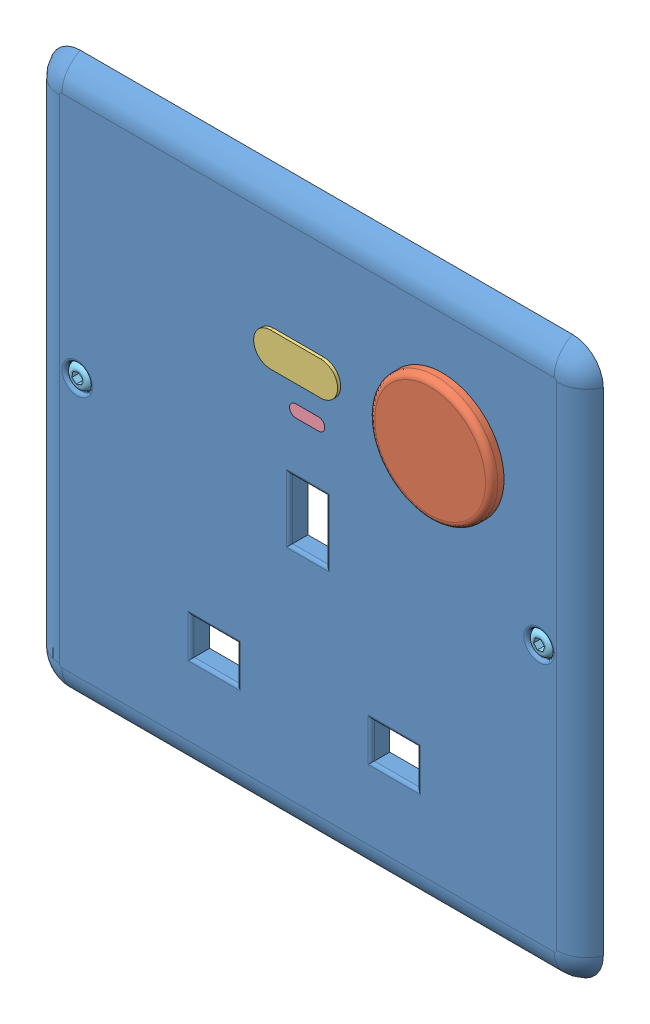
SolidWorks assembly OneSwitchAss, configuration Default. Lengths in mm.
Overall size (90 90 5).
6 component instances, 5 part files, 9 mates.
Components (placement in the parent):
- OneSwitch-1: OneSwitch [Default] at (-65.1599 0.035 9.5843) size (90 90 3)
- Button20mm-1: Button20mm [Default] at (12.0558 -2.4455 9.5843) x (0.673243 -0.739421 0) z (0 0 1) size (20 20 5)
- CoverFilter-1: CoverFilter [Default] at (31.6648 18.0079 12.7033) size (13.66 5.5 0.5)
- LEDindicator-1: LEDindicator [Default] at (15.6237 20.3006 9.5843) size (5.72 2 3)
- Screw4mm-1: Screw4mm [Default] at (-50.7894 -10.21 12.5843) x (-0.938133 -0.346274 0) z (0 0 -1) size (4 4 3)
- Screw4mm-2: Screw4mm [Default] at (24.0575 -4.8541 12.5843) x (-0.666788 0.745248 0) z (0 0 -1) size (4 4 3)
Mates (geometry in assembly coordinates):
- Concentric2: concentric anti-aligned: cylinder of OneSwitch-1 through (12.3917 13.0449 9.5843) axis (0 0 1) radius 10; cylinder of Button20mm-1 through (12.3917 13.0449 14.5843) axis (0 0 -1) radius 10
- Concentric3: concentric aligned: cylinder of OneSwitch-1 through (28.1038 -7.3722 9.5843) axis (0 0 1) radius 2; cylinder of Screw4mm-2 through (28.1038 -7.3722 9.5843) axis (0 0 1) radius 2
- Concentric4: concentric aligned: cylinder of OneSwitch-1 through (-46.9606 -7.3722 9.5843) axis (0 0 1) radius 2; cylinder of Screw4mm-1 through (-46.9606 -7.3722 9.5843) axis (0 0 1) radius 2
- Concentric5: concentric anti-aligned: cylinder of OneSwitch-1 through (-7.7365 5.7809 9.5843) axis (0 0 1) radius 1; cylinder of LEDindicator-1 through (-7.7365 5.7809 12.5843) axis (0 0 -1) radius 1
- Coincident1: coincident aligned: line of OneSwitch-1 through (-7.7365 6.7809 12.5843) axis (-1 0 0); line of LEDindicator-1 through (-7.7365 6.7809 12.5843) axis (-1 0 0)
- Coincident2: coincident aligned: circle of OneSwitch-1; circle of Button20mm-1
- Coincident4: coincident anti-aligned: circle of OneSwitch-1; circle of Screw4mm-2
- Coincident5: coincident anti-aligned: circle of OneSwitch-1; circle of Screw4mm-1
- Concentric6: concentric aligned: circle of OneSwitch-1; circle of CoverFilter-1
